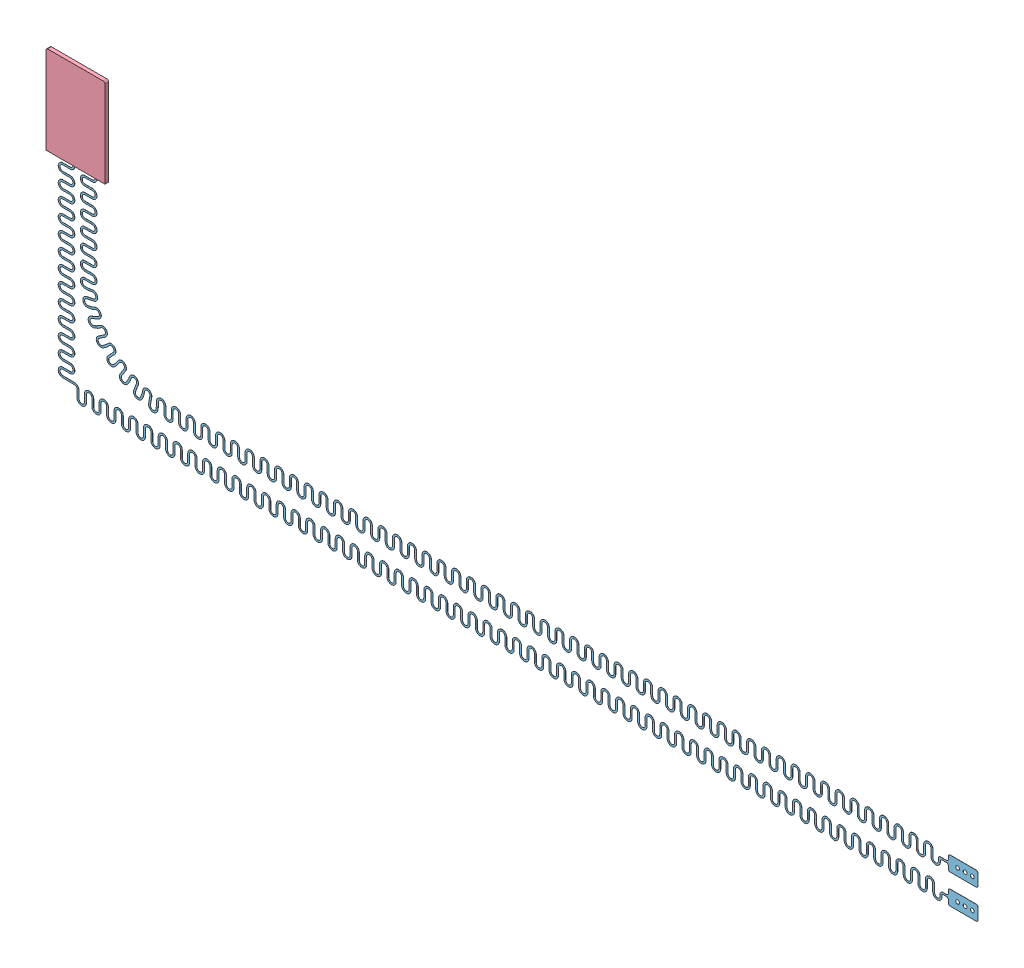
SolidWorks assembly Pressure_Sensor_Assembly-X01, configuration Default. Lengths in mm.
Overall size (126.06 39.88 0.5).
6 component instances, 5 part files, 16 mates.
Components (placement in the parent):
- Copper_Conductor-X01-1: Copper_Conductor-X01 [Default] at (-1.1461 6.2984 7.0607) size (5 7.5 0.02)
- Copper_Conductor-X01-2: Copper_Conductor-X01 [Default] at (-1.1461 6.2984 7.1657) x (-1 0 0) z (0 0 -1) size (5 7.5 0.02)
- PI_Insulator-X01-1: PI_Insulator-X01 [Default] at (-1.1461 6.2984 7.0757) size (5.5 5.5 0.03)
- PDMS_Dielectric-X01-1: PDMS_Dielectric-X01 [Spiral] at (-1.1461 6.2984 7.1007) x (0 1 0) z (0 0 1) size (4.5 4.5 0.05)
- PDMS_Encapsulation-Pressure_Sensor-X01-1: PDMS_Encapsulation-Pressure_Sensor-X01 [Default] at (-1.1461 6.2984 7.0607) size (8 12 0.51)
- Copper_Interconnects-Pressure-X01-1: Copper_Interconnects-Pressure-X01 [Default] at (-1.1461 1.5484 7.0757) x (0 1 0) z (0 0 1) size (33.12 124.69 0.02)
Mates (geometry in assembly coordinates):
- Parallel1: parallel anti-aligned: plane of Copper_Conductor-X01-1 through (-1.1461 6.2984 7.0757) normal (0 0 1); plane of Copper_Conductor-X01-2 through (-1.1461 6.2984 7.1507) normal (0 0 -1)
- Coincident2: coincident aligned: plane of Copper_Conductor-X01-1 through (-1.1461 8.7984 7.0757) normal (0 1 0); plane of Copper_Conductor-X01-2 through (-1.1461 8.7984 7.1507) normal (0 1 0)
- Coincident3: coincident aligned: plane of Copper_Conductor-X01-1 through (-3.6461 6.2984 7.0757) normal (-1 0 0); plane of Copper_Conductor-X01-2 through (-3.6461 6.2984 7.1507) normal (-1 0 0)
- Coincident4: coincident anti-aligned: plane of Copper_Conductor-X01-1 through (-1.1461 6.2984 7.0757) normal (0 0 1); plane of PI_Insulator-X01-1 through (-1.1461 6.2984 7.0757) normal (0 0 -1)
- Width1: width anti-aligned: plane of Copper_Conductor-X01-1 through (-3.6461 6.2984 7.0757) normal (-1 0 0); plane of Copper_Conductor-X01-1 through (1.3539 6.2984 7.0757) normal (1 0 0); plane of PI_Insulator-X01-1 through (1.6039 6.2984 7.1007) normal (1 0 0); plane of PI_Insulator-X01-1 through (-3.8961 6.2984 7.1007) normal (-1 0 0)
- Width2: width aligned: plane of PI_Insulator-X01-1 through (-1.1461 9.0484 7.1007) normal (0 1 0); plane of PI_Insulator-X01-1 through (-1.1461 3.5484 7.1007) normal (0 -1 0); plane of Copper_Conductor-X01-1 through (-1.1461 8.7984 7.0757) normal (0 1 0); plane of Copper_Conductor-X01-1 through (-1.1461 3.7984 7.0757) normal (0 -1 0)
- Coincident5: coincident anti-aligned: plane of PI_Insulator-X01-1 through (-1.1461 6.2984 7.1007) normal (0 0 1); plane of PDMS_Dielectric-X01-1 through (-1.1461 6.2984 7.1007) normal (0 0 -1)
- Coincident6: coincident anti-aligned: plane of Copper_Conductor-X01-1 through (-1.1461 6.2984 7.0607) normal (1 0 0); plane of PDMS_Dielectric-X01-1 through (-1.1461 6.2984 7.1007) normal (-1 0 0)
- Coincident8: coincident aligned: plane of Copper_Conductor-X01-1 through (-1.1461 6.2984 7.0607) normal (0 1 0); plane of PDMS_Dielectric-X01-1 through (-1.1461 6.2984 7.1007) normal (0 1 0)
- Coincident9: coincident anti-aligned: plane of Copper_Conductor-X01-2 through (-1.1461 6.2984 7.1507) normal (0 0 -1); plane of PDMS_Dielectric-X01-1 through (-1.1461 6.2984 7.1507) normal (0 0 1)
- Coincident10: coincident anti-aligned: plane of Copper_Conductor-X01-1 through (-1.1461 6.2984 7.0607) normal (0 0 -1); plane of PDMS_Encapsulation-X01-1 through (-1.1461 6.2984 7.0607) normal (0 0 1)
- Coincident11: coincident aligned: plane of Copper_Conductor-X01-1 through (-1.1461 6.2984 7.0607) normal (0 1 0); plane of PDMS_Encapsulation-X01-1 through (-1.1461 6.2984 7.0607) normal (0 1 0)
- Coincident12: coincident aligned: plane of Copper_Conductor-X01-1 through (-1.1461 6.2984 7.0607) normal (1 0 0); plane of PDMS_Encapsulation-X01-1 through (-1.1461 6.2984 7.0607) normal (1 0 0)
- Coincident13: coincident anti-aligned: plane of Copper_Conductor-X01-1 through (-1.1461 6.2984 7.0757) normal (0 0 1); plane of Copper_Interconnects-X01-1 through (-1.1461 1.5484 7.0757) normal (0 0 -1)
- Width3: width aligned: plane of Copper_Interconnects-Pressure-X01-1 through (-1.6461 -0.4516 7.0907) normal (1 0 0); plane of Copper_Interconnects-Pressure-X01-1 through (-3.6461 -0.4516 7.0907) normal (-1 0 0); plane of Copper_Conductor-X01-1 through (-1.6461 6.2984 7.0757) normal (1 0 0); plane of Copper_Conductor-X01-1 through (-3.6461 6.2984 7.0757) normal (-1 0 0)
- Distance1: distance = 2.25 mm anti-aligned: plane of Copper_Interconnects-X01-1 through (-1.6461 3.5484 7.0907) normal (0 1 0); plane of Copper_Conductor-X01-1 through (-1.1461 1.2984 7.0757) normal (0 -1 0)
